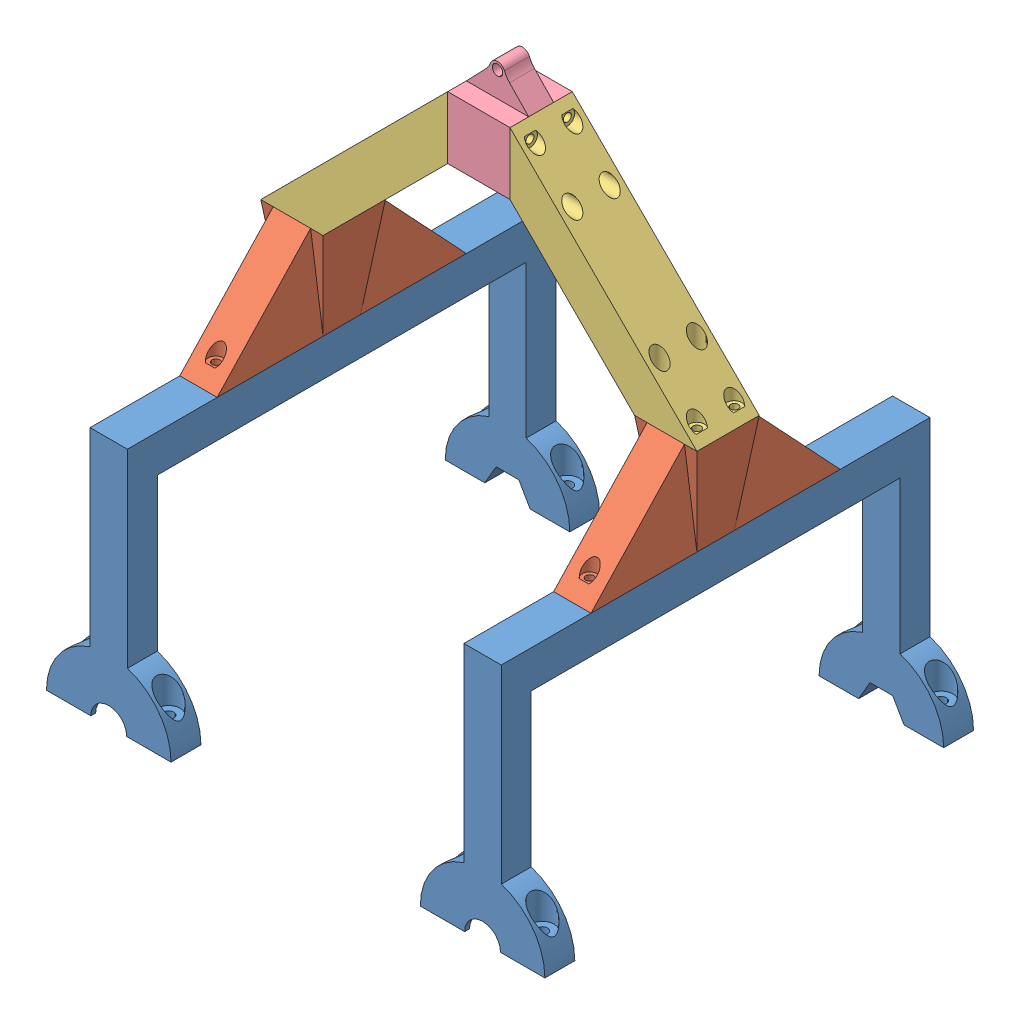
SolidWorks assembly Rocker_1.0, configuration Default. Lengths in mm.
Overall size (200 230 172).
7 component instances, 4 part files, 15 mates.
Components (placement in the parent):
- foot_1.0-1: foot_1.0 [Default] at (23.1128 115.6532 136.1153) size (50 100 172)
- foot_connect_1.0-1: foot_connect_1.0 [Default] at (23.1128 123.1532 136.1153) x (0 0 -1) z (1 0 0) size (100 40 25)
- Rocker_Bar_1.0-1: Rocker_Bar_1.0 [Default] at (85.6128 213.1532 123.6153) x (0 0 1) z (-1 0 0) size (25 75 75)
- Rocker_Pivot_1.0-1: Rocker_Pivot_1.0 [Default] at (98.1128 213.1532 136.1153) size (25 40 25)
- Rocker_Bar_1.0-2: Rocker_Bar_1.0 [Default] at (160.6128 163.1532 123.6153) x (0 0 1) z (0 1 0) size (25 75 75)
- foot_connect_1.0-2: foot_connect_1.0 [Default] at (173.1128 123.1532 136.1153) x (0.000001 0 -1) z (1 0 0.000001) size (100 40 25)
- foot_1.0-2: foot_1.0 [Default] at (173.1128 115.6532 136.1153) x (1 0 0.000001) z (-0.000001 0 1) size (50 100 172)
Mates (geometry in assembly coordinates):
- Concentric1: concentric: circle of foot_1.0-1; circle of foot_connect_1.0-1
- Coincident1: coincident: plane of foot_1.0-1 through (15.6128 123.1532 222.1153) normal (0 1 0); plane of foot_connect_1.0-1 through (23.1128 123.1532 136.1153) normal (0 -1 0)
- Coincident2: coincident: line of foot_connect_1.0-1 through (10.6128 163.1532 148.6153) axis (0 0 -1); line of Rocker_Bar_1.0-1 through (10.6128 163.1532 148.6153) axis (0 0 -1)
- Concentric2: concentric: cylinder of foot_connect_1.0-1 through (15.6128 163.1532 143.6153) axis (0 1 0) radius 2.5; cylinder of Rocker_Bar_1.0-1 through (15.6128 238.1542 143.6153) axis (0 -1 0) radius 1.6
- Concentric3: concentric: cylinder of Rocker_Bar_1.0-1 through (10.6118 233.1532 143.6153) axis (1 0 0) radius 1.6; cylinder of Rocker_Pivot_1.0-1 through (85.6128 233.1532 143.6153) axis (-1 0 0) radius 2.5
- Coincident3: coincident: plane of Rocker_Bar_1.0-1 through (85.6128 213.1532 148.6153) normal (0 0 1); plane of Rocker_Pivot_1.0-1 through (85.6128 238.1532 148.6153) normal (0 0 1)
- Coincident4: coincident: plane of foot_1.0-1 through (30.6128 123.1532 222.1153) normal (1 0 0); plane of foot_connect_1.0-1 through (30.6128 208.2226 136.1153) normal (1 0 0)
- Coincident5: coincident: line of Rocker_Pivot_1.0-1 through (110.6128 238.1532 148.6153) axis (0 -1 0); line of Rocker_Bar_1.0-2 through (110.6128 238.1532 148.6153) axis (0 -1 0)
- Concentric4: concentric: cylinder of Rocker_Pivot_1.0-1 through (110.6128 233.1532 143.6153) axis (1 0 0) radius 2.5; cylinder of Rocker_Bar_1.0-2 through (185.6138 233.1532 143.6153) axis (-1 0 0) radius 1.6
- Coincident6: coincident: plane of Rocker_Bar_1.0-1 through (85.6128 238.1532 148.6153) normal (1 0 0); plane of Rocker_Pivot_1.0-1 through (85.6128 238.1532 123.6153) normal (-1 0 0)
- Coincident7: coincident: moEndPointRef_w of Rocker_Bar_1.0-2; moEndPointRef_w of foot_connect_1.0-2
- Concentric5: concentric: circle of Rocker_Bar_1.0-2; cylinder of foot_connect_1.0-2 through (180.6128 163.1532 143.6153) axis (0 1 0) radius 2.5
- Concentric7: concentric: circle of foot_connect_1.0-2; circle of foot_1.0-2
- Coincident8: coincident: plane of foot_connect_1.0-2 through (173.1128 123.1532 136.1153) normal (0 -1 0); plane of foot_1.0-2 through (165.6127 123.1532 222.1153) normal (0 1 0)
- Coincident9: coincident: plane of foot_connect_1.0-2 through (180.6128 208.2226 136.1153) normal (1 0 0.000001); plane of foot_1.0-2 through (180.6127 123.1532 222.1153) normal (1 0 0.000001)
